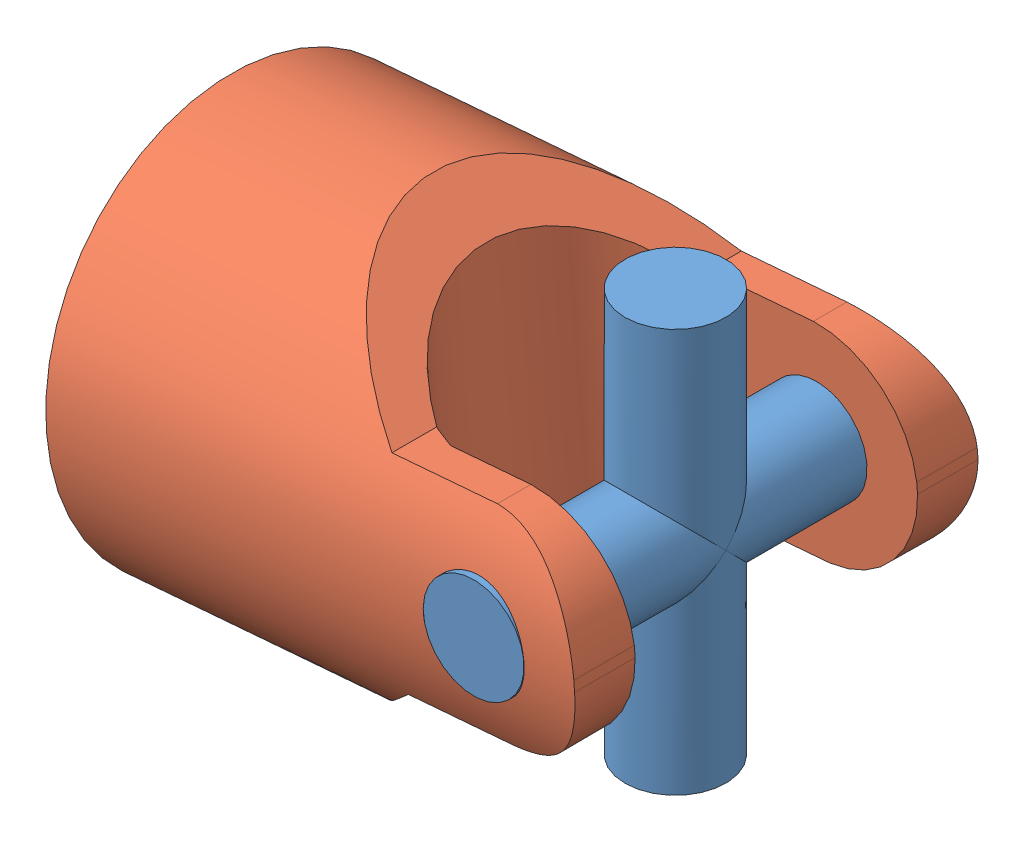
SolidWorks assembly 23406-116068, configuration Default. Lengths in mm.
Overall size (44.48 35.31 32).
2 component instances, 2 part files, 3 mates.
Components (placement in the parent):
- 23406-116068_02-1: 23406-116068_02 [Default] at (-2.4897 0.1066 2.1372) size (8 32 32)
- 23406-116068_03-1: 23406-116068_03 [Default] at (-2.4897 0.1066 2.1372) x (0.996679 0.081431 0) z (0 0 1) size (42.01 32 32)
Mates (geometry in assembly coordinates):
- Concentric1: concentric aligned: cylinder of 23406-116068_02-1 through (-2.4897 0.1066 2.1372) axis (0 0 -1) radius 4; cylinder of 23406-116068_03-1 through (-2.4897 0.1066 34.1372) axis (0 0 -1) radius 4
- Concentric2: concentric aligned: cylinder of 23406-116068_02-1 through (-2.4897 0.1066 2.1372) axis (0 0 -1) radius 4; cylinder of 23406-116068_03-1 through (-2.4897 0.1066 34.1372) axis (0 0 -1) radius 4
- Width1: width: plane of 23406-116068_02-1 through (-0.4897 0.1066 -13.8628) normal (0 0 -1); plane of 23406-116068_02-1 through (-0.4897 0.1066 18.1372) normal (0 0 1); cylinder of 23406-116068_03-1 through (-15.4465 -0.952 2.1372) axis (-0.996679 -0.081431 0) radius 16
